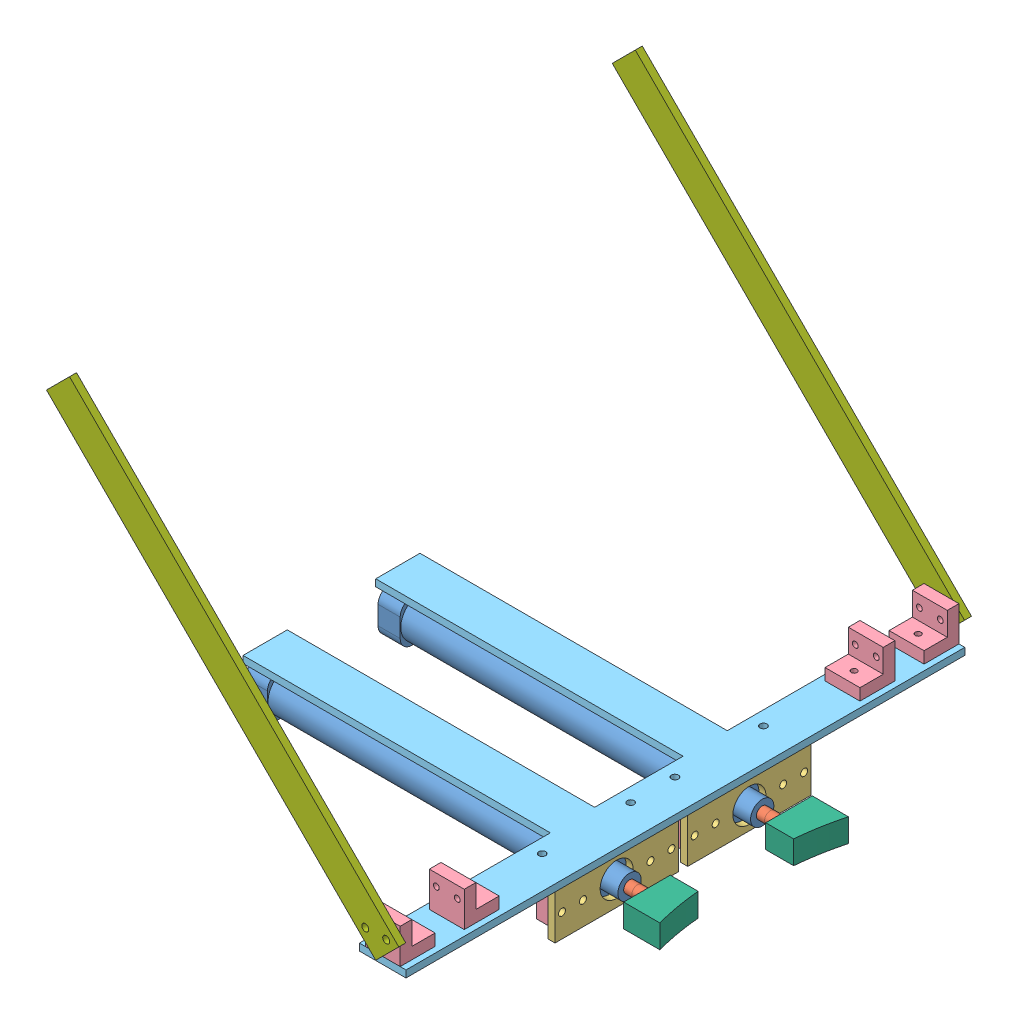
SolidWorks assembly a推环装置（装配体）, configuration 默认. Lengths in mm.
Overall size (181.53 174.42 246).
24 component instances, 7 part files, 37 mates.
Components (placement in the parent):
- 推环装置（单）-1: 推环装置（单） [默认] at (49.431 27.8208 7.0325) size (175.5 18 18)
  - 16x100标准型-1: 16x100标准型 [默认] at (-234.5005 -21.5583 173.7409) x (0 0 -1) z (1 0 0) size (18 18 175.5)
    - 16x100标准型壳-1: 16x100标准型壳 [默认] at (-1.7591 0.557 78) size (18 18 156)
    - 16x100标准型轴-1: 16x100标准型轴 [默认] at (-1.7591 0.557 87.5) x (0.935449 -0.353463 0) z (0 0 1) size (5 5 166)
- 气缸固定前板-1: 气缸固定前板 [默认] at (40.4305 -2.6805 209.0325) size (3 20 53)
- 单孔角码-1: 单孔角码 [默认] at (25.4305 12.3195 171.0325) x (0 0 -1) z (0 -1 0) size (15 15 15)
- 单孔角码-2: 单孔角码 [默认] at (25.4305 12.3195 209.0325) x (0 0 -1) z (0 -1 0) size (15 15 15)
- 气缸固定下板-1: 气缸固定下板 [默认] at (44.4305 20.3195 331.0325) x (0 -1 0) z (0 0 1) size (3 152 240)
- 推环装置（带角码）左-1: 推环装置（带角码）左 [默认] at (105.9959 -119.1176 146.3018) size (181.03 20 53)
  - 推环装置（单）-1: 推环装置（单） [默认] at (-56.5649 147.9384 -82.2692) size (175.5 18 18)
    - 16x100标准型-1: 16x100标准型 [默认] at (-234.5005 -21.5583 173.7409) x (0 0 -1) z (1 0 0) size (18 18 175.5)
      - 16x100标准型壳-1: 16x100标准型壳 [默认] at (-1.7591 0.557 78) size (18 18 156)
      - 16x100标准型轴-1: 16x100标准型轴 [默认] at (-1.7591 0.557 87.5) x (0.935449 -0.353463 0) z (0 0 1) size (5 5 166)
  - 单孔角码-1: 单孔角码 [默认] at (-80.5654 131.4371 119.7308) x (0 0 -1) z (0 -1 0) size (15 15 15)
  - 气缸固定前板-1: 气缸固定前板 [默认] at (-65.5654 136.4371 66.7308) x (1 0 0) z (0 0 -1) size (3 20 53)
  - 单孔角码-2: 单孔角码 [默认] at (-80.5654 131.4371 81.7308) x (0 0 -1) z (0 -1 0) size (15 15 15)
  - 推环块-1: 推环块 [默认] at (-47.5654 121.9371 75.2308) x (0 1 0) z (0 0 -1) size (10 15.53 20)
- 单孔角码-3: 单孔角码 [默认] at (41.9305 25.3195 316.0325) x (-1 0 0) z (0 1 0) size (15 15 15)
- 单孔角码-4: 单孔角码 [默认] at (26.9305 25.3195 106.0325) x (1 0 0) z (0 1 0) size (15 15 15)
- 推环装置支撑架-1: 推环装置支撑架 [默认] at (34.4305 20.42 91.0325) x (0 0 -1) z (-0.707107 -0.707107 0) size (3 200 14)
- 推环装置支撑架-2: 推环装置支撑架 [默认] at (34.4305 20.42 334.0325) x (0 0 -1) z (-0.707107 -0.707107 0) size (3 200 14)
- 推环块-1: 推环块 [默认] at (58.4305 11.8195 200.5325) x (0 -1 0) z (0 0 1) size (10 15.53 20)
- 单孔角码-5: 单孔角码 [默认] at (26.9305 25.3195 133.5525) x (1 0 0) z (0 1 0) size (15 15 15)
- 单孔角码-6: 单孔角码 [默认] at (41.9305 25.3195 288.5125) x (-1 0 0) z (0 1 0) size (15 15 15)
Mates (geometry in assembly coordinates):
- 同心1: concentric aligned: circle of 推环装置（单）-1/16x100标准型-1/16x100标准型壳-1; circle of 气缸固定前板-1
- 重合1: coincident anti-aligned: plane of 推环装置（单）-1/16x100标准型-1/16x100标准型壳-1 through (40.4305 6.8195 182.5325) normal (1 0 0); plane of 气缸固定前板-1 through (40.4305 -2.6805 209.0325) normal (-1 0 0)
- 同心2: concentric aligned: circle of 气缸固定前板-1; circle of 单孔角码-2
- 同心3: concentric aligned: circle of 气缸固定前板-1; circle of 单孔角码-2
- 重合2: coincident anti-aligned: plane of 气缸固定前板-1 through (40.4305 -2.6805 209.0325) normal (-1 0 0); plane of 单孔角码-2 through (40.4305 12.3195 209.0325) normal (1 0 0)
- 同心4: concentric anti-aligned: cylinder of 气缸固定前板-1 through (43.4305 7.3195 159.0325) axis (-1 0 0) radius 1.5; circle of 单孔角码-1
- 同心5: concentric aligned: circle of 气缸固定前板-1; circle of 单孔角码-1
- 重合3: coincident anti-aligned: plane of 气缸固定前板-1 through (40.4305 -2.6805 209.0325) normal (-1 0 0); plane of 单孔角码-1 through (40.4305 12.3195 171.0325) normal (1 0 0)
- 同心6: concentric anti-aligned: circle of 单孔角码-1; cylinder of 气缸固定下板-1 through (30.4305 17.3195 163.5325) axis (0 1 0) radius 1.5
- 同心7: concentric aligned: circle of 单孔角码-2; circle of 气缸固定下板-1
- 重合4: coincident anti-aligned: plane of 单孔角码-2 through (35.4305 17.3195 209.0325) normal (0 1 0); plane of 气缸固定下板-1 through (44.4305 17.3195 331.0325) normal (0 -1 0)
- 同心8: concentric aligned: circle of 气缸固定下板-1; circle of 推环装置（带角码）左-1/单孔角码-2
- 同心9: concentric aligned: circle of 气缸固定下板-1; circle of 推环装置（带角码）左-1/单孔角码-1
- 重合5: coincident anti-aligned: plane of 气缸固定下板-1 through (44.4305 17.3195 331.0325) normal (0 -1 0); plane of 推环装置（带角码）左-1/单孔角码-1 through (35.4305 17.3195 266.0325) normal (0 1 0)
- 重合6: coincident anti-aligned: plane of 气缸固定下板-1 through (44.4305 20.3195 331.0325) normal (0 1 0); plane of 单孔角码-4 through (26.9305 20.3195 96.0325) normal (0 -1 0)
- 平行1: parallel anti-aligned: plane of 气缸固定下板-1 through (44.4305 17.3195 331.0325) normal (0 0 1); plane of 单孔角码-4 through (26.9305 25.3195 91.0325) normal (0 0 -1)
- 同心13: concentric aligned: cylinder of 气缸固定下板-1 through (34.4305 17.3195 101.0325) axis (0 1 0) radius 1.5; circle of 单孔角码-4
- 同心14: concentric aligned: cylinder of 气缸固定下板-1 through (34.4305 17.3195 321.0325) axis (0 1 0) radius 1.5; circle of 单孔角码-3
- 重合8: coincident anti-aligned: plane of 气缸固定下板-1 through (44.4305 20.3195 331.0325) normal (0 1 0); plane of 单孔角码-3 through (41.9305 20.3195 326.0325) normal (0 -1 0)
- 平行2: parallel aligned: plane of 气缸固定下板-1 through (44.4305 17.3195 331.0325) normal (0 0 1); plane of 单孔角码-3 through (41.9305 25.3195 331.0325) normal (0 0 1)
- 平行3: parallel aligned: plane of 气缸固定下板-1 through (44.4305 17.3195 91.0325) normal (0 0 -1); plane of 单孔角码-4 through (26.9305 25.3195 91.0325) normal (0 0 -1)
- 同心15: concentric aligned: circle of 单孔角码-4; circle of 推环装置支撑架-1
- 同心16: concentric aligned: circle of 单孔角码-4; circle of 推环装置支撑架-1
- 同心17: concentric anti-aligned: circle of 单孔角码-3; circle of 推环装置支撑架-2
- 同心18: concentric anti-aligned: circle of 单孔角码-3; circle of 推环装置支撑架-2
- 重合9: coincident anti-aligned: plane of 单孔角码-3 through (41.9305 25.3195 331.0325) normal (0 0 1); plane of 推环装置支撑架-2 through (34.4305 20.42 331.0325) normal (0 0 -1)
- 重合10: coincident anti-aligned: plane of 单孔角码-4 through (26.9305 25.3195 91.0325) normal (0 0 -1); plane of 推环装置支撑架-1 through (34.4305 20.42 91.0325) normal (0 0 1)
- 平行4: parallel anti-aligned: plane of 推环装置（单）-1/16x100标准型-1/16x100标准型壳-1 through (40.4305 15.8195 191.5325) normal (0 1 0); plane of 气缸固定下板-1 through (44.4305 17.3195 331.0325) normal (0 -1 0)
- 同心19: concentric aligned: cylinder of 推环装置（单）-1/16x100标准型-1/16x100标准型轴-1 through (68.4305 6.8195 182.5325) axis (-1 0 0) radius 2.5; cylinder of 推环块-1 through (68.4305 6.8195 182.5325) axis (-1 0 0) radius 3
- 平行5: parallel aligned: line of 气缸固定前板-1 through (43.4305 -2.6805 209.0325) axis (0 0 -1); line of 推环块-1 through (58.4305 1.8195 190.5325) axis (0 0 -1)
- 重合12: coincident anti-aligned: plane of 推环装置（单）-1/16x100标准型-1/16x100标准型轴-1 through (68.4305 6.8195 182.5325) normal (1 0 0); plane of 推环块-1 through (68.4305 6.8195 182.5325) normal (-1 0 0)
- 同心20: concentric anti-aligned: circle of 气缸固定下板-1; circle of 单孔角码-5
- 平行6: parallel aligned: line of 气缸固定下板-1 through (44.4305 20.3195 91.0325) axis (0 0 1); line of 单孔角码-5 through (41.9305 20.3195 118.5525) axis (0 0 1)
- 重合14: coincident anti-aligned: plane of 气缸固定下板-1 through (44.4305 20.3195 331.0325) normal (0 1 0); plane of 单孔角码-5 through (26.9305 20.3195 123.5525) normal (0 -1 0)
- 同心21: concentric anti-aligned: circle of 气缸固定下板-1; circle of 单孔角码-6
- 平行7: parallel: plane of 气缸固定下板-1 through (44.4305 17.3195 331.0325) normal (1 0 0); line of 单孔角码-6 through (41.9305 20.3195 303.5125) axis (0 0 -1)
- 重合16: coincident anti-aligned: plane of 气缸固定下板-1 through (44.4305 20.3195 331.0325) normal (0 1 0); plane of 单孔角码-6 through (41.9305 20.3195 298.5125) normal (0 -1 0)
